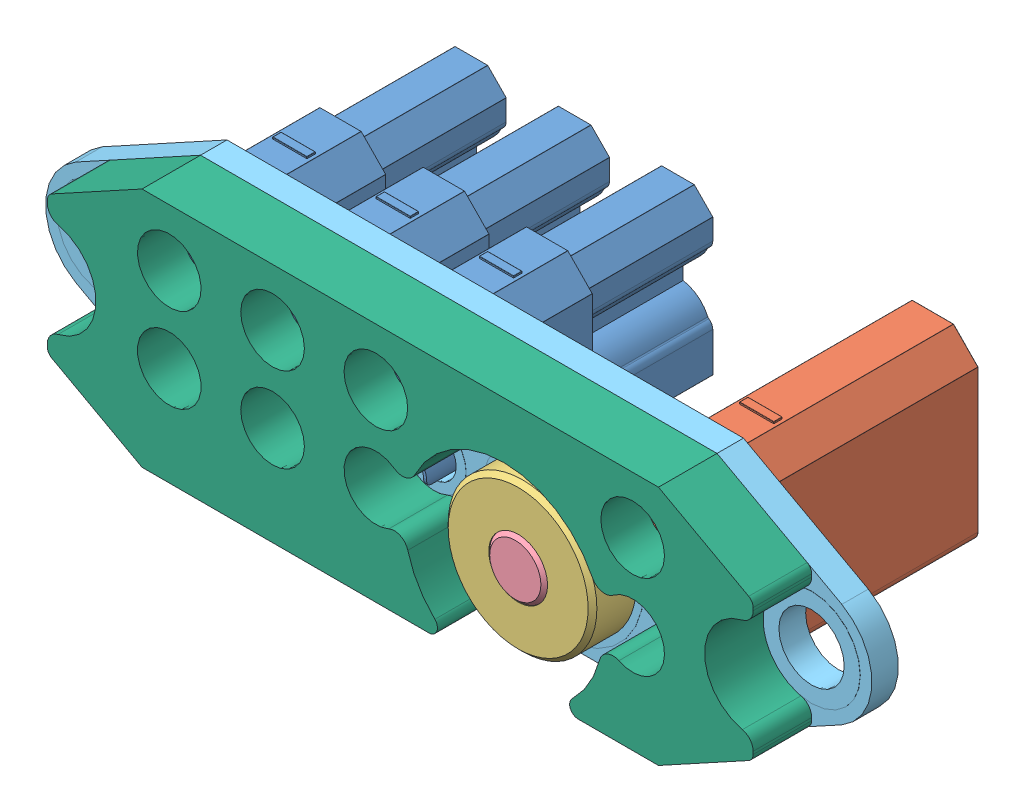
SolidWorks assembly Switch+PD+Board+V1 (1) (1).stp, configuration Default. Lengths in mm.
Overall size (48 14 17.55).
8 component instances, 6 part files, 0 mates.
Components (placement in the parent):
- XT30_Female.stp-1: XT30_Female.stp [Default] at (-4.7913 -1.9356 -6.5462) x (-1 0 0) z (0 0 -1) size (5.25 10.45 15.6)
- XT30_Male.stp-1: XT30_Male.stp [Default] at (4.8749 -1.9112 -14.0462) size (5.25 10.45 15.5)
- 8-32 PEM Nut Insert.stp-1: 8-32 PEM Nut Insert.stp [Default] at (0 0 2.5496) x (1 0 0) z (0 1 0) size (8.64 3.94 8.64)
- XT30_Female.stp-2: XT30_Female.stp [Default] at (-10.7913 -1.9356 -6.5462) x (-1 0 0) z (0 0 -1) size (5.25 10.45 15.6)
- XT30_Female.stp-3: XT30_Female.stp [Default] at (-16.7913 -1.9356 -6.5462) x (-1 0 0) z (0 0 -1) size (5.25 10.45 15.6)
- 8-32 3-16 NO THREADS_ Button Head Hex Drive Screw.stp-1: 8-32 3-16 NO THREADS_ Button Head Hex Drive Screw.stp [Default] at (0 0 -0.7693) x (-1 0 0) z (0 0 -1) size (7.92 7.92 6.97)
- Switch PD Board V1.3 Top Connectors.stp-1: Switch PD Board V1.3 Top Connectors.stp [Default] at origin size (48 14 1.56)
- Switch PD Board V1.3 Top Connectors-0.stp-1: Switch PD Board V1.3 Top Connectors-0.stp [Default] at origin size (41 14 3.4)
